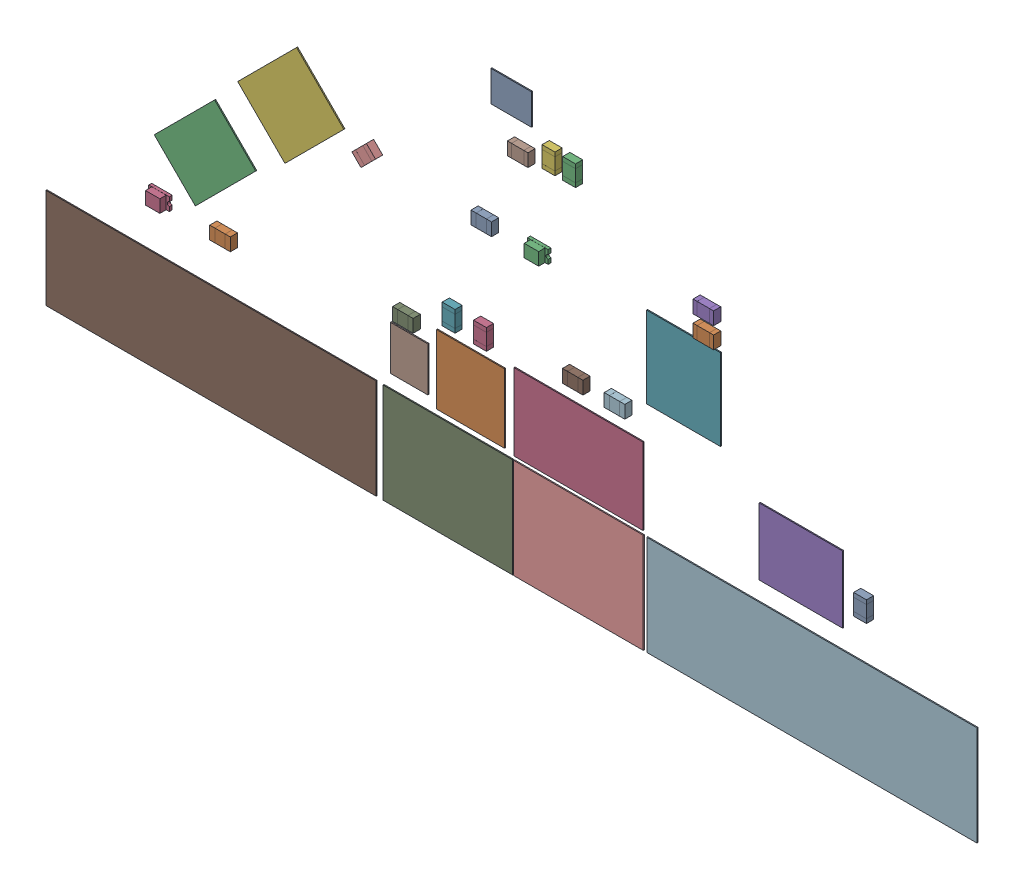
SolidWorks assembly Packages.step, configuration Default. Lengths in mm.
Overall size (90.52 41.61 0.9).
28 component instances, 12 part files, 0 mates.
Components (placement in the parent):
- PQFN50P300X250X97-14N.step-1: PQFN50P300X250X97-14N.step [Default] at (0 -15.24 1.5525) size (3.95 2.99 0.1)
- AP220533YR13.step-1: AP220533YR13.step [Default] at (-4.191 -41.275 1.5525) x (-1 0 0) z (0 0 1) size (6.6 6.7 0.1)
- CUS-12B.step-1: CUS-12B.step [Default] at (-30.48 -34.29 1.5525) x (-0.707107 -0.707107 0) z (0 0 1) size (8.3 5.65 0.1)
- OS102011MS2QS1.step-1: OS102011MS2QS1.step [Default] at (4.318 -41.021 1.5525) size (12.55 7.45 0.1)
- PTS526SM15SMTR2LFS.step-1: PTS526SM15SMTR2LFS.step [Default] at (27.94 -40.64 1.5525) size (8.1 6.5 0.1)
- PTS526SM15SMTR2LFS.step-2: PTS526SM15SMTR2LFS.step [Default] at (-21.59 -26.67 1.5525) x (0.707107 0.707107 0) z (0 0 1) size (8.1 6.5 0.1)
- SOP65P640X120-20N.step-1: SOP65P640X120-20N.step [Default] at (16.51 -30.48 1.5525) x (0 -1 0) z (0 0 1) size (7.9 7.17 0.1)
- SOT95P285X140-3N.step-1: SOT95P285X140-3N.step [Default] at (-10.16 -42.164 1.5525) x (0 -1 0) z (0 0 1) size (4.3 3.65 0.1)
- TB00250002BE.step-1: TB00250002BE.step [Default] at (-8.89 -50.8 1.5525) size (12.6 9.7 0.1)
- TB00250002BE.step-2: TB00250002BE.step [Default] at (3.81 -50.8 1.5525) size (12.6 9.7 0.1)
- TB00250006BE.step-1: TB00250006BE.step [Default] at (-41.91 -50.8 1.5525) size (32.1 9.7 0.1)
- TB00250006BE.step-2: TB00250006BE.step [Default] at (16.51 -50.8 1.5525) size (32.1 9.7 0.1)
- C0805.step-1: C0805.step [Default] at (34.29 -40.64 1.5525) x (0 -1 0) z (0 0 1) size (2 1.25 0.7)
- C0805.step-2: C0805.step [Default] at (19.05 -25.4 1.5525) size (2 1.25 0.7)
- C0805.step-3: C0805.step [Default] at (6 -18.08 1.5525) x (0 -1 0) z (0 0 1) size (2 1.25 0.7)
- C0805.step-4: C0805.step [Default] at (-2.667 -36.195 1.5525) x (0 1 0) z (0 0 1) size (2 1.25 0.7)
- C0805.step-5: C0805.step [Default] at (19.05 -23.368 1.5525) size (2 1.25 0.7)
- C0805.step-6: C0805.step [Default] at (4 -18.08 1.5525) x (0 -1 0) z (0 0 1) size (2 1.25 0.7)
- C0805.step-7: C0805.step [Default] at (-5.715 -36.195 1.5525) x (0 1 0) z (0 0 1) size (2 1.25 0.7)
- C0805.step-8: C0805.step [Default] at (1 -19.08 1.5525) size (2 1.25 0.7)
- R0805.step-1: R0805.step [Default] at (-10.16 -38.608 1.5525) x (-1 0 0) z (0 0 1) size (2 1.25 0.7)
- R0805.step-2: R0805.step [Default] at (-13.97 -26.67 1.5525) x (0.707107 0.707107 0) z (0 0 1) size (2 1.25 0.7)
- R0805.step-3: R0805.step [Default] at (6.35 -35.56 1.5525) x (-1 0 0) z (0 0 1) size (2 1.25 0.7)
- R0805.step-4: R0805.step [Default] at (10.414 -35.56 1.5525) x (-1 0 0) z (0 0 1) size (2 1.25 0.7)
- R0805.step-5: R0805.step [Default] at (-2.54 -26.67 1.5525) x (-1 0 0) z (0 0 1) size (2 1.25 0.7)
- R0805.step-6: R0805.step [Default] at (-27.94 -40.64 1.5525) size (2 1.25 0.7)
- CHIP-LED0805.step-1: CHIP-LED0805.step [Default] at (2.54 -26.67 1.5525) x (0 1 0) z (0 0 1) size (1.25 2 0.9)
- CHIP-LED0805.step-2: CHIP-LED0805.step [Default] at (-34.29 -40.64 1.5525) x (0 -1 0) z (0 0 1) size (1.25 2 0.9)
